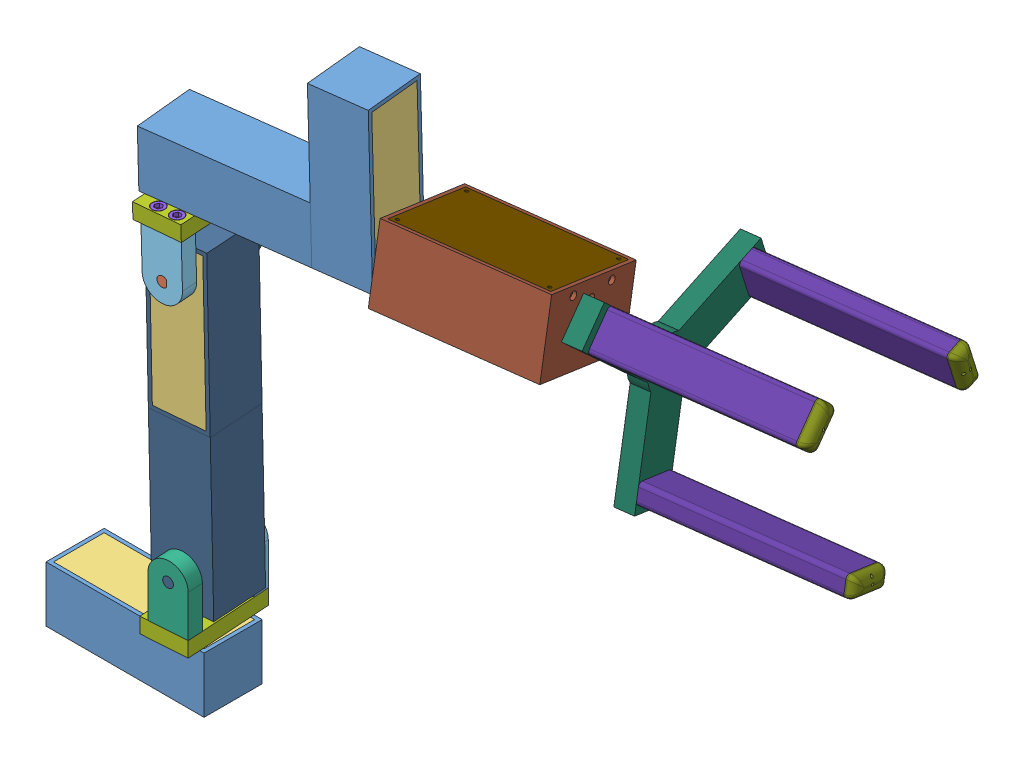
SolidWorks assembly 5DOFArm, configuration Default. Lengths in mm.
Overall size (640.63 545.52 233.12).
72 component instances, 18 part files, 18 mates.
Components (placement in the parent):
- Case1WithBearings-2: Case1WithBearings [Default] at (15.7322 41.1423 -46.3275) size (125 56 46)
  - Motor1WithCase-1: Motor1WithCase [Default] at (-7.1067 -6.2049 -11.0572) size (125 56 46)
    - ArmBase-1: ArmBase [Default] at (40.6555 43.6092 113.8063) size (125 44 46)
    - WormGearMotor-2: WormGearMotor [Default] at (-17.0445 63.1092 113.8063) x (0 0 -1) z (0 -1 0) size (40 117.2 52)
    - ArmBaseCover-2: ArmBaseCover [Default] at (40.6555 87.6092 113.8063) x (-1 0 0) z (0 0 1) size (119 4.5 40)
  - SB608ZZ-1: SB608ZZ [Default] at (73.0487 85.4044 102.7492) x (0 -1 0) z (0 0 1) size (7 22 22)
- ConnectingJoint-2: ConnectingJoint [Default] at (102.3983 127.6243 64.5417) x (-0.997794 0 0.066385) z (-0.066385 0 -0.997794) size (36 60 68.86)
  - BearingJoints-1: BearingJoints [Default] at (10.0484 39.9223 31.0061) size (30 48 12)
  - BearingJoints2-1: BearingJoints2 [Default] at (10.0484 39.9223 -12.9939) x (-1 0 0) z (0 0 -1) size (30 48 12)
  - JointBottom-1: JointBottom [Default] at (13.0484 -5.0777 9.0061) x (0 0 -1) z (1 0 0) size (68 12 36)
  - socket head cap screw_iso-1: socket head cap screw_iso [ISO 4762 M6 x 20 - 20S] at (3.0484 -5.0777 -18.9939) x (0 1 0) z (-0.488199 0 0.872732) size (26 10 10)
  - socket head cap screw_iso-2: socket head cap screw_iso [ISO 4762 M6 x 20 - 20S] at (3.0484 -5.0777 37.0061) x (0 1 0) z (0 0 1) size (26 10 10)
  - socket head cap screw_iso-3: socket head cap screw_iso [ISO 4762 M6 x 20 - 20S] at (17.0484 -5.0777 37.0061) x (0 1 0) z (0 0 1) size (26 10 10)
  - socket head cap screw_iso-4: socket head cap screw_iso [ISO 4762 M6 x 20 - 20S] at (17.0484 -5.0777 -18.9939) x (0 1 0) z (-0.513591 0 0.858035) size (26 10 10)
  - M5X10-1: M5X10 [Default] at (22.2578 2.0842 9.2195) x (-1 0 0) z (0 -0.924225 -0.381849) size (15 8.5 8.5)
- Motor2WithCase-1: Motor2WithCase [Default] at (-47.603 293.7622 69.7076) x (-0.058955 -0.919135 -0.389507) z (0.725988 -0.307288 0.615236) size (139.16 102.77 112.77)
  - WormGearMotor-2: WormGearMotor [Default] at (22.8097 94.5076 102.0809) x (0.052143 -0.73415 -0.676982) z (-0.392561 -0.6384 0.662074) size (40 117.2 52)
  - ArmBaseCover-2: ArmBaseCover [Default] at (85.4103 96.8062 104.4099) x (-0.918247 0.231235 -0.321487) z (-0.052143 0.73415 0.676982) size (119 4.5 40)
  - ArmBase2-1: ArmBase2 [Default] at (68.1376 68.7166 133.5411) x (0.918247 -0.231235 0.321487) z (-0.052143 0.73415 0.676982) size (125 56 46)
- Motor2WithCase-2: Motor2WithCase [Default] at (-47.0319 239.5556 61.2454) x (-0.045079 0.916958 0.396428) z (0.624695 0.335546 -0.705099) size (139.16 102.77 112.77)
  - WormGearMotor-2: WormGearMotor [Default] at (22.8097 94.5076 102.0809) x (0.052143 -0.73415 -0.676982) z (-0.392561 -0.6384 0.662074) size (40 117.2 52)
  - ArmBaseCover-2: ArmBaseCover [Default] at (85.4103 96.8062 104.4099) x (-0.918247 0.231235 -0.321487) z (-0.052143 0.73415 0.676982) size (119 4.5 40)
  - ArmBase2-1: ArmBase2 [Default] at (68.1376 68.7166 133.5411) x (0.918247 -0.231235 0.321487) z (-0.052143 0.73415 0.676982) size (125 56 46)
- ConnectingJoint-3: ConnectingJoint [Default] at (95.9091 411.6737 46.9214) x (-0.997453 -0.026156 0.066362) z (0.066385 0 0.997794) size (36 60 68.86)
  - BearingJoints-1: BearingJoints [Default] at (10.0484 39.9223 31.0061) size (30 48 12)
  - BearingJoints2-1: BearingJoints2 [Default] at (10.0484 39.9223 -12.9939) x (-1 0 0) z (0 0 -1) size (30 48 12)
  - JointBottom-1: JointBottom [Default] at (13.0484 -5.0777 9.0061) x (0 0 -1) z (1 0 0) size (68 12 36)
  - socket head cap screw_iso-1: socket head cap screw_iso [ISO 4762 M6 x 20 - 20S] at (3.0484 -5.0777 -18.9939) x (0 1 0) z (-0.488199 0 0.872732) size (26 10 10)
  - socket head cap screw_iso-2: socket head cap screw_iso [ISO 4762 M6 x 20 - 20S] at (3.0484 -5.0777 37.0061) x (0 1 0) z (0 0 1) size (26 10 10)
  - socket head cap screw_iso-3: socket head cap screw_iso [ISO 4762 M6 x 20 - 20S] at (17.0484 -5.0777 37.0061) x (0 1 0) z (0 0 1) size (26 10 10)
  - socket head cap screw_iso-4: socket head cap screw_iso [ISO 4762 M6 x 20 - 20S] at (17.0484 -5.0777 -18.9939) x (0 1 0) z (-0.513591 0 0.858035) size (26 10 10)
  - M5X10-1: M5X10 [Default] at (22.2578 2.0842 9.2195) x (-1 0 0) z (0 -0.924225 -0.381849) size (15 8.5 8.5)
- Case1WithBearings-3: Case1WithBearings [Default] at (143.6843 499.6054 -52.5763) x (-0.994706 -0.026142 0.099381) z (0.099392 0.000867 0.995048) size (125 56 46)
  - Motor1WithCase-1: Motor1WithCase [Default] at (-7.1067 -6.2049 -11.0572) size (125 56 46)
    - ArmBase-1: ArmBase [Default] at (40.6555 43.6092 113.8063) size (125 44 46)
    - WormGearMotor-2: WormGearMotor [Default] at (-17.0445 63.1092 113.8063) x (0 0 -1) z (0 -1 0) size (40 117.2 52)
    - ArmBaseCover-2: ArmBaseCover [Default] at (40.6555 87.6092 113.8063) x (-1 0 0) z (0 0 1) size (119 4.5 40)
  - SB608ZZ-1: SB608ZZ [Default] at (73.0487 85.4044 102.7492) x (0 -1 0) z (0 0 1) size (7 22 22)
- Case1WithBearings-4: Case1WithBearings [Default] at (134.8938 514.0238 -51.7108) x (0.026098 -0.999658 -0.001736) z (0.099392 0.000867 0.995048) size (125 56 46)
  - Motor1WithCase-1: Motor1WithCase [Default] at (-7.1067 -6.2049 -11.0572) size (125 56 46)
    - ArmBase-1: ArmBase [Default] at (40.6555 43.6092 113.8063) size (125 44 46)
    - WormGearMotor-2: WormGearMotor [Default] at (-17.0445 63.1092 113.8063) x (0 0 -1) z (0 -1 0) size (40 117.2 52)
    - ArmBaseCover-2: ArmBaseCover [Default] at (40.6555 87.6092 113.8063) x (-1 0 0) z (0 0 1) size (119 4.5 40)
  - SB608ZZ-1: SB608ZZ [Default] at (73.0487 85.4044 102.7492) x (0 -1 0) z (0 0 1) size (7 22 22)
- GrapperWithServos-1: GrapperWithServos [Default] at (369.9289 377.5137 22.5389) x (0.091322 0.218565 0.97154) z (-0.994706 -0.026142 0.099381) size (170.88 147.99 355)
  - ServoHolder-1: ServoHolder [Default] at (20.6091 41.5283 66.4389) size (76 55.75 187)
  - ServoWithHornCover-1: ServoWithHornCover [Default] at (-47.2507 32.9202 59.0729) x (0 0 -1) z (1 0 0) size (60.01 49.75 41.52) (flexible)
    - MG996R-1: MG996R [Default] at (22.884 11.6081 50.6098) size (53.5 42.75 19.5)
    - ServoHornWithGroove-1: ServoHornWithGroove [Default] at (12.384 56.3581 50.6098) x (0.653288 0 0.75711) z (0.75711 0 -0.653288) size (30 9.5 30)
    - ServoCover-1: ServoCover [Default] at (34.0772 41.3581 67.8598) x (-1 0 0) z (0 0 -1) size (57.5 20 34.5)
  - ServoWithHornCover-2: ServoWithHornCover [Default] at (-12.7507 32.9202 59.0729) x (0 0 -1) z (1 0 0) size (60.01 49.75 41.52) (flexible)
    - MG996R-1: MG996R [Default] at (22.884 11.6081 50.6098) size (53.5 42.75 19.5)
    - ServoHornWithGroove-1: ServoHornWithGroove [Default] at (12.384 56.3581 50.6098) x (0.586538 0 0.809922) z (0.809922 0 -0.586538) size (30 9.5 30)
    - ServoCover-1: ServoCover [Default] at (34.0772 41.3581 67.8598) x (-1 0 0) z (0 0 -1) size (57.5 20 34.5)
  - 3GripperAssembly-1: 3GripperAssembly [Default] at (-30.3334 -49.3942 19.9719) x (1 0 0) z (0 1 0) size (170.88 173 147.99)
    - EndEffector3Grapper-1: EndEffector3Grapper [Default] at (50.9425 60.533 115.9226) size (170.88 20 147.99)
    - FingerAssembly-1: FingerAssembly [Default] at (105.0348 198.5242 138.6511) x (-0.5 0 0.866025) z (0 1 0) size (30 15 158)
      - FingerTip-1: FingerTip [Default] at (7.3627 17.1904 24.0088) size (30 15 11)
      - Finger-1: Finger [Default] at (7.3627 18.2904 -122.9912) x (1 0 0) z (0 -1 0) size (30 150 15)
    - FingerAssembly-2: FingerAssembly [Default] at (4.2129 198.5242 151.4036) x (-0.5 0 -0.866025) z (0 1 0) size (30 15 158)
      - FingerTip-1: FingerTip [Default] at (7.3627 17.1904 24.0088) size (30 15 11)
      - Finger-1: Finger [Default] at (7.3627 18.2904 -122.9912) x (1 0 0) z (0 -1 0) size (30 150 15)
    - FingerAssembly-3: FingerAssembly [Default] at (43.5799 198.5242 57.713) x (1 0 0) z (0 1 0) size (30 15 158)
      - FingerTip-1: FingerTip [Default] at (7.3627 17.1904 24.0088) size (30 15 11)
      - Finger-1: Finger [Default] at (7.3627 18.2904 -122.9912) x (1 0 0) z (0 -1 0) size (30 150 15)
  - ServoWithHornCover-4: ServoWithHornCover [Default] at (-30.0007 32.9202 119.5729) x (0 0 -1) z (1 0 0) size (60.01 49.75 41.52)
    - MG996R-1: MG996R [Default] at (22.884 11.6081 50.6098) size (53.5 42.75 19.5)
    - ServoHornWithGroove-1: ServoHornWithGroove [Default] at (12.384 56.3581 50.6098) x (-0.837169 0 -0.546944) z (-0.546944 0 0.837169) size (30 9.5 30)
    - ServoCover-1: ServoCover [Default] at (34.0772 41.3581 67.8598) x (-1 0 0) z (0 0 -1) size (57.5 20 34.5)
  - ServoHolderCover-1: ServoHolderCover [Default] at (20.6091 94.2783 66.4389) x (0 0 -1) z (1 0 0) size (118 3 70)
  - socket head cap screw_iso-1: socket head cap screw_iso [ISO 4762 M6 x 20 - 20S] at (20.6091 66.5283 -55.5611) x (0 0 1) z (-0.923728 -0.383049 0) size (26 10 10)
- M5X10-1: M5X10 [Default] at (235.9941 452.4719 39.713) x (0.047119 -0.975472 0.215021) z (0.997291 0.058112 0.04509) size (15 8.5 8.5)
Mates (geometry in assembly coordinates):
- Concentric4: concentric aligned: cylinder of Case1WithBearings-2/SB608ZZ-1 through (88.7809 119.8466 56.4217) axis (0 -1 0) radius 11; cylinder of ConnectingJoint-2/JointBottom-1 through (88.7809 126.5466 56.4217) axis (0 -1 0) radius 11
- Coincident4: coincident anti-aligned: plane of Case1WithBearings-2/SB608ZZ-1 through (99.4809 126.5466 56.4217) normal (0 1 0); plane of ConnectingJoint-2/JointBottom-1 through (88.7809 126.5466 56.4217) normal (0 -1 0)
- Concentric5: concentric anti-aligned: cylinder of ConnectingJoint-2/BearingJoints-1 through (90.0483 167.5466 30.2799) axis (0.066385 0 0.997794) radius 11; cylinder of Motor2WithCase-1/WormGearMotor-2 through (90.8449 167.5466 42.2534) axis (-0.066385 0 -0.997794) radius 4
- Coincident5: coincident anti-aligned: plane of ConnectingJoint-2/BearingJoints-1 through (90.3138 167.5466 34.2711) normal (0.066385 0 0.997794); plane of Motor2WithCase-1/ArmBaseCover-2 through (89.4913 207.038 34.3258) normal (-0.066385 0 -0.997794)
- Coincident6: coincident aligned: plane of Motor2WithCase-1/ArmBase2-1 through (111.134 270.0044 32.8859) normal (0.997577 0.020871 -0.06637); plane of Motor2WithCase-2/ArmBase2-1 through (114.0549 270.0044 76.7888) normal (0.997577 0.020871 -0.06637)
- Coincident7: coincident aligned: plane of Motor2WithCase-1/ArmBaseCover-2 through (89.4913 207.038 34.3258) normal (-0.066385 0 -0.997794); plane of Motor2WithCase-2/ArmBase2-1 through (86.8882 332.0108 34.499) normal (-0.066385 0 -0.997794)
- Coincident8: coincident anti-aligned: plane of Motor2WithCase-1/ArmBase2-1 through (111.134 270.0044 32.8859) normal (-0.020824 0.999782 0.001385); plane of Motor2WithCase-2/ArmBase2-1 through (114.0549 270.0044 76.7888) normal (0.020824 -0.999782 -0.001385)
- Concentric6: concentric anti-aligned: cylinder of Motor2WithCase-2/WormGearMotor-2 through (88.4555 371.5022 70.4743) axis (0.066385 0 0.997794) radius 4; cylinder of ConnectingJoint-3/BearingJoints-1 through (89.2521 371.5022 82.4478) axis (-0.066385 0 -0.997794) radius 11
- Coincident9: coincident anti-aligned: plane of Motor2WithCase-2/ArmBase2-1 through (86.8882 332.0108 34.499) normal (-0.066385 0 -0.997794); plane of ConnectingJoint-3/BearingJoints2-1 through (86.0656 371.5022 34.5537) normal (0.066385 0 0.997794)
- Concentric7: concentric aligned: cylinder of ConnectingJoint-3/JointBottom-1 through (83.4637 412.4097 56.7754) axis (-0.026098 0.999658 0.001736) radius 11; cylinder of Case1WithBearings-3/SB608ZZ-1 through (83.2888 419.1074 56.7871) axis (-0.026098 0.999658 0.001736) radius 11
- Coincident10: coincident anti-aligned: plane of ConnectingJoint-3/JointBottom-1 through (83.3593 416.4083 56.7824) normal (-0.026098 0.999658 0.001736); plane of Case1WithBearings-3/Motor1WithCase-1/ArmBase-1 through (122.6502 417.4409 52.8569) normal (0.026098 -0.999658 -0.001736)
- Coincident11: coincident anti-aligned: plane of Case1WithBearings-3/Motor1WithCase-1/ArmBase-1 through (187.1053 419.0947 69.5317) normal (0.994706 0.026142 -0.099381); plane of Case1WithBearings-4/Motor1WithCase-1/ArmBase-1 through (183.1882 481.5534 46.7541) normal (-0.994706 -0.026142 0.099381)
- Coincident12: coincident aligned: plane of Case1WithBearings-3/Motor1WithCase-1/ArmBase-1 through (122.6502 417.4409 52.8569) normal (0.026098 -0.999658 -0.001736); plane of Case1WithBearings-4/Motor1WithCase-1/ArmBase-1 through (230.8724 420.245 65.1589) normal (0.026098 -0.999658 -0.001736)
- Coincident13: coincident aligned: plane of Case1WithBearings-3/Motor1WithCase-1/ArmBase-1 through (187.1053 419.0947 69.5317) normal (0.099392 0.000867 0.995048); plane of Case1WithBearings-4/Motor1WithCase-1/ArmBase-1 through (227.6101 545.2022 65.376) normal (0.099392 0.000867 0.995048)
- Concentric8: concentric aligned: cylinder of Case1WithBearings-4/SB608ZZ-1 through (225.3004 443.1466 42.5811) axis (-0.994706 -0.026142 0.099381) radius 11; cylinder of GrapperWithServos-1/ServoHolder-1 through (231.9649 443.3217 41.9152) axis (-0.994706 -0.026142 0.099381) radius 11
- Coincident14: coincident anti-aligned: plane of Case1WithBearings-4/SB608ZZ-1 through (232.2442 432.6254 41.8967) normal (0.994706 0.026142 -0.099381); plane of GrapperWithServos-1/ServoHolder-1 through (231.9649 443.3217 41.9152) normal (-0.994706 -0.026142 0.099381)
- Concentric9: concentric aligned: cylinder of GrapperWithServos-1/ServoHolder-1 through (235.8286 456.1205 38.6727) axis (-0.047119 0.975472 -0.215021) radius 4.25; cylinder of M5X10-1 through (235.8286 456.1205 38.6727) axis (-0.047119 0.975472 -0.215021) radius 4.25
- Coincident15: coincident anti-aligned: plane of GrapperWithServos-1/ServoHolder-1 through (235.8286 456.1205 38.6727) normal (-0.047119 0.975472 -0.215021); plane of M5X10-1 through (236.0686 455.2182 34.5266) normal (0.047119 -0.975472 0.215021)
